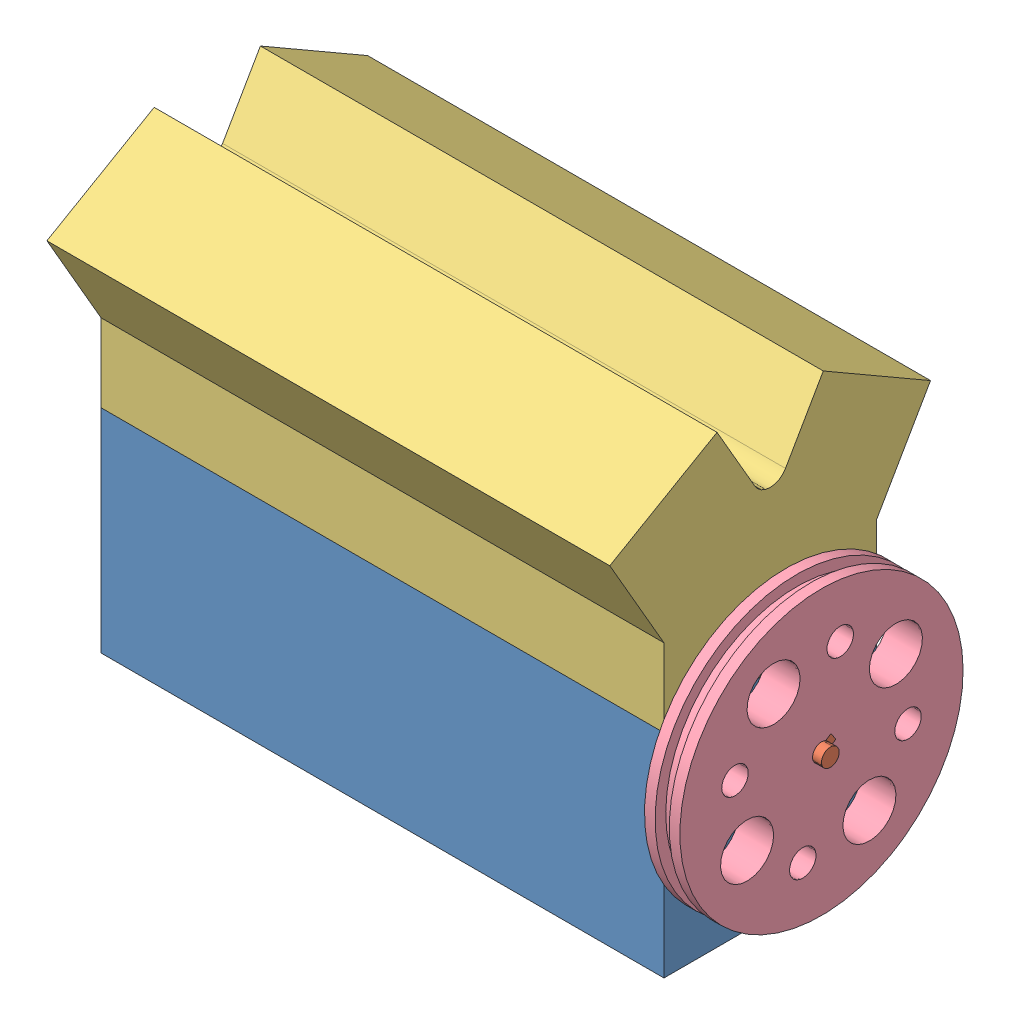
SolidWorks assembly Assem4, configuration Default. Lengths in mm.
Overall size (490.22 339.8 280.86).
4 component instances, 4 part files, 11 mates.
Components (placement in the parent):
- V6_EngineBase-1: V6_EngineBase [Default] at (327.454 115.7861 238.2902) size (403.86 215.9 152.4)
- V6_Crank_Shaft-1: V6_Crank_Shaft [Default] at (294.434 236.4361 314.4902) x (0 -0.84069 -0.541516) z (1 0 0) size (76.2 76.2 490.22)
- V6_EngineHead-1: V6_EngineHead [Default] at (-76.406 268.1861 314.4902) x (0 0 1) z (-1 0 0) size (230.12 167.62 403.86)
- V6_FLYWHEEL-1: V6_FLYWHEEL [Default] at (338.884 236.4361 314.4902) x (0 -0.84069 -0.541516) z (1 0 0) size (203.2 203.2 25.4)
Mates (geometry in assembly coordinates):
- Concentric1: concentric anti-aligned: cylinder of V6_EngineBase-1 through (327.455 236.4361 314.4902) axis (-1 0 0) radius 6.985; cylinder of V6_Crank_Shaft-1 through (-119.586 236.4361 314.4902) axis (1 0 0) radius 6.985
- Concentric2: concentric anti-aligned: cylinder of V6_EngineBase-1 through (263.954 236.4361 314.4902) axis (1 0 0) radius 6.35; cylinder of V6_Crank_Shaft-1 through (370.634 236.4361 314.4902) axis (-1 0 0) radius 6.35
- Width1: width aligned: plane of V6_Crank_Shaft-1 through (370.634 236.4361 314.4902) normal (1 0 0); plane of V6_Crank_Shaft-1 through (-119.586 236.4361 314.4902) normal (-1 0 0); plane of V6_EngineBase-1 through (327.454 115.7861 390.6902) normal (1 0 0); plane of V6_EngineBase-1 through (-76.406 115.7861 390.6902) normal (-1 0 0)
- Concentric3: concentric aligned: cylinder of V6_EngineBase-1 through (314.754 331.6861 250.9902) axis (0 -1 0) radius 5.715; cylinder of V6_EngineHead-1 through (314.754 344.3861 250.9902) axis (0 -1 0) radius 6.35
- Concentric4: concentric aligned: cylinder of V6_EngineBase-1 through (-63.706 331.6861 377.9902) axis (0 -1 0) radius 5.715; cylinder of V6_EngineHead-1 through (-63.706 344.3861 377.9902) axis (0 -1 0) radius 6.35
- Coincident3: coincident anti-aligned: plane of V6_EngineBase-1 through (327.454 268.1861 390.6902) normal (0 1 0); plane of V6_EngineHead-1 through (327.454 268.1861 238.2902) normal (0 -1 0)
- Concentric5: concentric anti-aligned: cylinder of V6_Crank_Shaft-1 through (370.634 236.4361 314.4902) axis (-1 0 0) radius 6.35; cylinder of V6_FLYWHEEL-1 through (321.104 236.4361 314.4902) axis (1 0 0) radius 6.427
- Coincident4: coincident anti-aligned: plane of V6_Crank_Shaft-1 through (294.434 241.9379 305.9488) normal (0 0.541516 -0.84069); plane of V6_FLYWHEEL-1 through (321.104 244.6071 307.6681) normal (0 -0.541516 0.84069)
- Coincident5: coincident anti-aligned: plane of V6_Crank_Shaft-1 through (364.284 213.1346 344.8021) normal (0 -0.84069 -0.541516); plane of V6_FLYWHEEL-1 through (321.104 236.7929 308.0731) normal (0 0.84069 0.541516)
- Coincident6: coincident anti-aligned: plane of V6_Crank_Shaft-1 through (364.284 218.473 348.2407) normal (0 0.84069 0.541516); plane of V6_FLYWHEEL-1 through (321.104 242.1313 311.5118) normal (0 -0.84069 -0.541516)
- Width2: width aligned: plane of V6_FLYWHEEL-1 through (364.284 236.4361 314.4902) normal (1 0 0); plane of V6_FLYWHEEL-1 through (338.884 236.4361 314.4902) normal (-1 0 0); plane of V6_Crank_Shaft-1 through (364.284 213.1346 344.8021) normal (1 0 0); plane of V6_Crank_Shaft-1 through (338.884 213.1346 344.8021) normal (-1 0 0)
